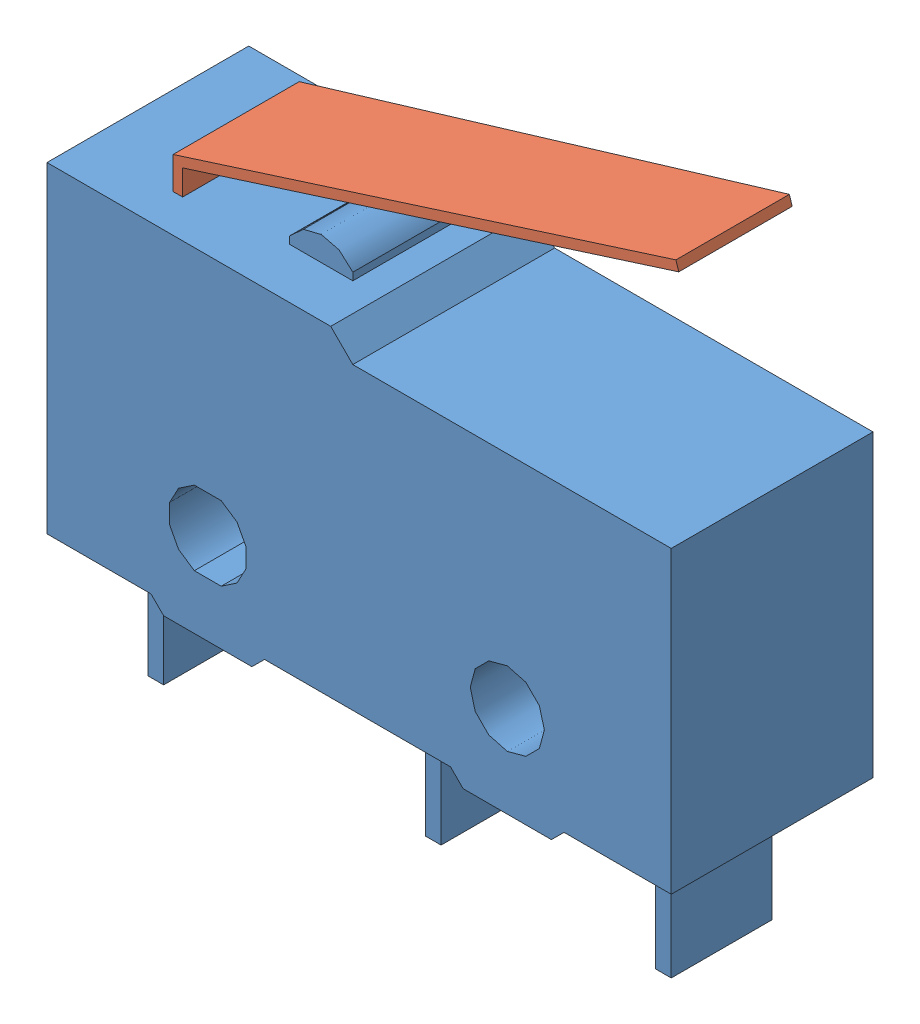
SolidWorks assembly SS_01GL_E, configuration Default. Lengths in mm.
Overall size (19.8 20 6.4).
2 component instances, 2 part files, 1 mates.
Components (placement in the parent):
- SS_01GL_E_BASE-1: SS_01GL_E_BASE [Default] at origin size (19.8 14.87 6.4)
- SS_01GL_E_ACTUATOR-1: SS_01GL_E_ACTUATOR [Default] at (-11.5 7.7 0) size (15.84 5.9 4)
Mates (geometry in assembly coordinates):
- Distance4: distance = 13.6 mm anti-aligned: plane of SS_01GL_E_BASE-1; line of SS_01GL_E_ACTUATOR-1 through (3.9483 13.6 1.8) axis (0 0 -1)
